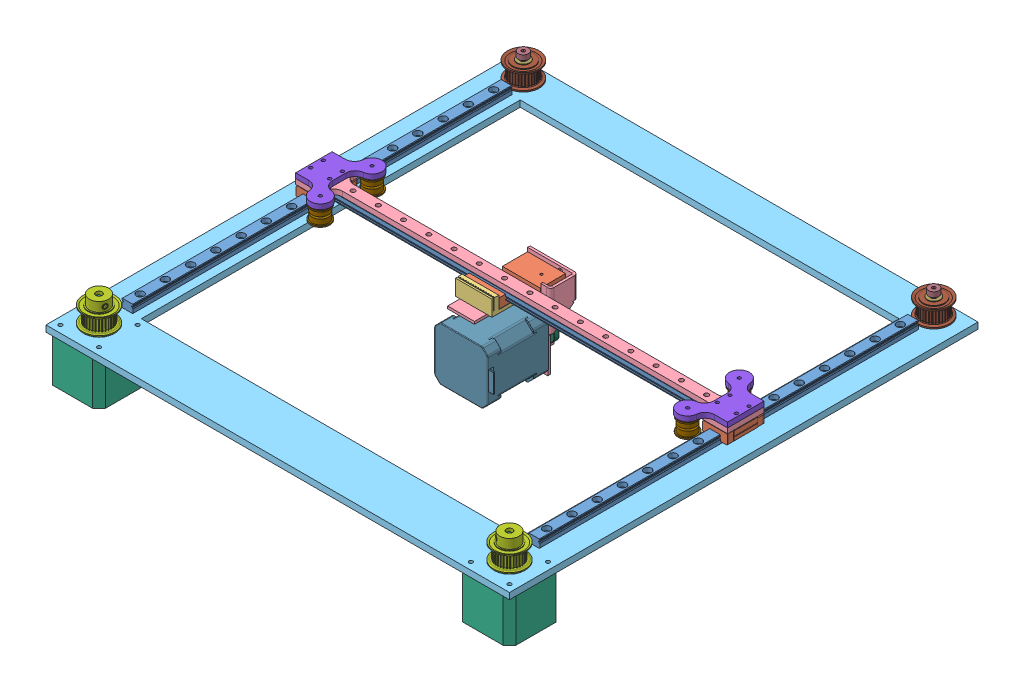
SolidWorks assembly XY, configuration Default. Lengths in mm.
Overall size (367 74.55 374.3).
68 component instances, 22 part files, 46 mates.
Components (placement in the parent):
- Y Rail-1: Y Rail [Default] at (-8.0434 -13.2339 12.0464) size (20 10.1 300)
  - MGN9-300MM-1: MGN9-300MM [Default] at (68.4102 185.8946 388.0774) size (9 6.6 300)
  - MGN9-1: MGN9 [Default] at (68.4102 185.8946 227.9447) size (20 8.05 28.9)
- Y Rail-2: Y Rail [Default] at (313.9566 -13.2339 12.0464) size (20 10.1 300)
  - MGN9-300MM-1: MGN9-300MM [Default] at (68.4102 185.8946 388.0774) size (9 6.6 300)
  - MGN9-1: MGN9 [Default] at (68.4102 185.8946 227.9447) size (20 8.05 28.9)
- X Rail-1: X Rail [Default] at (456.9443 355.5553 308.4012) x (0 0 -1) z (-1 0 0) size (25.38 12.6 300)
  - MGN9-300MM-1: MGN9-300MM [Default] at (68.4102 185.8946 388.0774) size (9 6.6 300)
  - MGN9-1: MGN9 [Default] at (68.4102 185.8946 264.6487) size (20 8.05 28.9)
  - X Carriage-1: X Carriage [Default] at (68.4102 189.3946 264.6487) x (1 0 0) z (0 1 0) size (25.38 28.9 12.5)
- X Support-1: X Support [Default] at (60.3668 176.1607 239.991) x (1 0 0) z (0 1 0) size (342 28.9 4)
- XY PLate-1: XY PLate [Default] at (378.8668 162.1607 597.6238) x (1 0 0) z (0 -1 0) size (367 371 5)
- Nema17-1: Nema17 [Default] at (77.8477 127.4107 443.2623) x (1 0 0) z (0 1 0) size (42 42 57.75)
- GT32TPulley-1: GT32TPulley [Default] at (58.8668 180.0607 418.6238) x (0.954377 0 0.298606) z (0 1 0) size (25.4 25.4 20.6)
- Nema17-2: Nema17 [Default] at (402.8477 127.4107 443.2623) x (1 0 0) z (0 1 0) size (42 42 57.75)
- GT32TPulley-2: GT32TPulley [Default] at (383.8668 180.0607 418.6238) x (-0.801635 0 -0.597814) z (0 1 0) size (25.4 25.4 20.6)
- BearingMount-1: BearingMount [Default] at (60.3668 180.1607 239.991) x (1 0 0) z (0 1 0) size (33.44 56.76 4)
- Idler Assembly-1: Idler Assembly [Default] at (85.5746 172.2269 208.7013) x (0 1 0) z (0 0 1) size (13.2 19.59 19.59)
  - F624ZZ-1: F624ZZ [Default] at (7.719 9.6467 10.7874) size (5 15 15)
  - M4 Washer-1: M4 Washer [Default] at (1.3338 9.6467 10.7874) x (0 -1 0) z (0 0 1) size (8.85 0.8 8.85)
  - M4 Washer-2: M4 Washer [Default] at (0.5338 9.6467 10.7874) x (0 -1 0) z (0 0 1) size (8.85 0.8 8.85)
  - F624ZZ-3: F624ZZ [Default] at (-5.0514 9.6467 10.7874) x (-1 0 0) z (0 -0.924225 -0.381849) size (5 15 15)
  - M4 Washer-3: M4 Washer [Default] at (-5.2662 9.6467 10.7874) x (0 -1 0) z (0 0 1) size (8.85 0.8 8.85)
  - M4 Washer-4: M4 Washer [Default] at (7.1338 9.6467 10.7874) x (0 -1 0) z (0 0 1) size (8.85 0.8 8.85)
- Idler Assembly-2: Idler Assembly [Default] at (85.5746 172.2269 249.7059) x (0 1 0) z (0 0 1) size (13.2 19.59 19.59)
  - F624ZZ-1: F624ZZ [Default] at (7.719 9.6467 10.7874) size (5 15 15)
  - M4 Washer-1: M4 Washer [Default] at (1.3338 9.6467 10.7874) x (0 -1 0) z (0 0 1) size (8.85 0.8 8.85)
  - M4 Washer-2: M4 Washer [Default] at (0.5338 9.6467 10.7874) x (0 -1 0) z (0 0 1) size (8.85 0.8 8.85)
  - F624ZZ-3: F624ZZ [Default] at (-5.0514 9.6467 10.7874) x (-1 0 0) z (0 -0.924225 -0.381849) size (5 15 15)
  - M4 Washer-3: M4 Washer [Default] at (-5.2662 9.6467 10.7874) x (0 -1 0) z (0 0 1) size (8.85 0.8 8.85)
  - M4 Washer-4: M4 Washer [Default] at (7.1338 9.6467 10.7874) x (0 -1 0) z (0 0 1) size (8.85 0.8 8.85)
- BearingMount-2: BearingMount [Default] at (382.3668 184.1607 239.991) x (-1 0 0) z (0 -1 0) size (33.44 56.76 4)
- Idler Assembly-3: Idler Assembly [Default] at (357.1591 174.8945 208.7013) x (0 -1 0) z (0 0 1) size (13.2 19.59 19.59)
  - F624ZZ-1: F624ZZ [Default] at (7.719 9.6467 10.7874) size (5 15 15)
  - M4 Washer-1: M4 Washer [Default] at (1.3338 9.6467 10.7874) x (0 -1 0) z (0 0 1) size (8.85 0.8 8.85)
  - M4 Washer-2: M4 Washer [Default] at (0.5338 9.6467 10.7874) x (0 -1 0) z (0 0 1) size (8.85 0.8 8.85)
  - F624ZZ-3: F624ZZ [Default] at (-5.0514 9.6467 10.7874) x (-1 0 0) z (0 -0.924225 -0.381849) size (5 15 15)
  - M4 Washer-3: M4 Washer [Default] at (-5.2662 9.6467 10.7874) x (0 -1 0) z (0 0 1) size (8.85 0.8 8.85)
  - M4 Washer-4: M4 Washer [Default] at (7.1338 9.6467 10.7874) x (0 -1 0) z (0 0 1) size (8.85 0.8 8.85)
- Idler Assembly-4: Idler Assembly [Default] at (357.1591 174.8945 249.7059) x (0 -1 0) z (0 0 1) size (13.2 19.59 19.59)
  - F624ZZ-1: F624ZZ [Default] at (7.719 9.6467 10.7874) size (5 15 15)
  - M4 Washer-1: M4 Washer [Default] at (1.3338 9.6467 10.7874) x (0 -1 0) z (0 0 1) size (8.85 0.8 8.85)
  - M4 Washer-2: M4 Washer [Default] at (0.5338 9.6467 10.7874) x (0 -1 0) z (0 0 1) size (8.85 0.8 8.85)
  - F624ZZ-3: F624ZZ [Default] at (-5.0514 9.6467 10.7874) x (-1 0 0) z (0 -0.924225 -0.381849) size (5 15 15)
  - M4 Washer-3: M4 Washer [Default] at (-5.2662 9.6467 10.7874) x (0 -1 0) z (0 0 1) size (8.85 0.8 8.85)
  - M4 Washer-4: M4 Washer [Default] at (7.1338 9.6467 10.7874) x (0 -1 0) z (0 0 1) size (8.85 0.8 8.85)
- Y Idler-1: Y Idler [Default] at (38.2356 173.3081 63.6616) x (0 -1 0) z (0 0 1) size (14.3 25 25)
  - Y Axis Idlergpa32gt2090_a_h6_2_03-1: Y Axis Idlergpa32gt2090_a_h6_2_03 [Default] at (-0.0026 20.6312 18.9623) size (13.3 25 25)
  - GFM-0506-06-1: GFM-0506-06 [Default] at (7.1474 20.6312 18.9623) x (0 0 1) z (-1 0 0) size (10 10 6)
  - GFM-0506-06-2: GFM-0506-06 [Default] at (-7.1526 20.6312 18.9623) x (0 0 -1) z (1 0 0) size (10 10 6)
- M4x16mmshoulderscrew-1: M4x16mmshoulderscrew [Default] at (58.8668 186.1607 82.6238) x (0 -1 0) z (0 0 1) size (25 8 8)
- Y Idler-2: Y Idler [Default] at (356.2237 173.3133 87.2143) x (0 1 0) z (0.546944 0 -0.837169) size (14.3 25 25)
  - Y Axis Idlergpa32gt2090_a_h6_2_03-1: Y Axis Idlergpa32gt2090_a_h6_2_03 [Default] at (-0.0026 20.6312 18.9623) size (13.3 25 25)
  - GFM-0506-06-1: GFM-0506-06 [Default] at (7.1474 20.6312 18.9623) x (0 0 1) z (-1 0 0) size (10 10 6)
  - GFM-0506-06-2: GFM-0506-06 [Default] at (-7.1526 20.6312 18.9623) x (0 0 -1) z (1 0 0) size (10 10 6)
- M4x16mmshoulderscrew-2: M4x16mmshoulderscrew [Default] at (383.8668 186.1607 82.6238) x (0 -1 0) z (0 0 1) size (25 8 8)
- Production drive 1-1: Production drive 1 [Default] at (202.0208 138.0107 227.1016) size (46.3 64.5 70)
  - 400515-1: 400515 [Default] at origin size (46.3 42.3 70)
  - Bearing 3ID 10OD 4W-1: Bearing 3ID 10OD 4W [Default] at (12.205 0 -10) size (11.5 11.5 4)
  - Part1-2: Part1 [Default] at (0 0 -10) size (12.17 12.03 4)
  - Filament-1: Filament [Default] at (5.6 0 -10) x (0 0 -1) z (1 0 0) size (1.71 50 1.71)
  - 51115K100-1: 51115K100 [51115K1] at (5.6 -24.95 -10) x (0 1 0) z (1 0 0) size (17.94 9.24 8)
  - Scoop-1: Scoop [Default] at (5.6 6 -10) x (0.994129 0 0.1082) z (-0.1082 0 0.994129) size (9.24 12 8)
  - Cooler-1: Cooler [Default] at (-0.3 29.5 -10) x (1 0 0) z (0 0 -1) size (30 14 20)
  - 51115K100-2: 51115K100 [51115K1] at (-10.1812 8.8 -4.8812) x (0 1 0) z (0.997081 0 0.076353) size (17.94 9.24 8)
  - 51115K100-3: 51115K100 [51115K1] at (-10.1812 8.8 -15.1188) x (0 1 0) z (0.997081 0 0.076353) size (17.94 9.24 8)
  - Stud connector-1: Stud connector [Default] at (5.6 21 -10) x (0.951034 0 0.309086) z (0.309086 0 -0.951034) size (9.24 15 8)
  - Part9^Production drive 1-1: Part9^Production drive 1 [Default] at (0 0 -2) x (-1 0 0) z (0 -1 0) size (43.3 60 60.15) (virtual)
Mates (geometry in assembly coordinates):
- Coincident1: coincident aligned: plane of Y Rail-1/MGN9-300MM-1 through (64.4668 172.6607 100.1238) normal (0 1 0); plane of Y Rail-2/MGN9-300MM-1 through (386.4668 172.6607 100.1238) normal (0 1 0)
- Coincident2: coincident aligned: plane of Y Rail-1/MGN9-300MM-1 through (60.3668 172.6607 397.6238) normal (0 0 1); plane of Y Rail-2/MGN9-300MM-1 through (382.3668 172.6607 397.6238) normal (0 0 1)
- Coincident3: coincident aligned: plane of Y Rail-1/MGN9-1 through (60.3668 176.1607 239.991) normal (0 1 0); plane of X Rail-1/MGN9-300MM-1 through (368.8668 176.1607 244.491) normal (0 1 0)
- Distance1: distance = 1 mm anti-aligned: plane of X Rail-1/MGN9-300MM-1 through (71.3668 169.6607 239.991) normal (-1 0 0); plane of Y Rail-1/MGN9-1 through (70.3668 175.8607 230.541) normal (1 0 0)
- Distance2: distance = 9.95 mm aligned: plane of Y Rail-1/MGN9-1 through (60.3668 172.6607 254.441) normal (0 0 1); plane of X Rail-1/MGN9-300MM-1 through (368.8668 170.0607 244.491) normal (0 0 1)
- Distance3: distance = 1 mm anti-aligned: plane of Y Rail-2/MGN9-1 through (372.3668 172.6607 239.991) normal (-1 0 0); plane of X Rail-1/MGN9-300MM-1 through (371.3668 171.4075 243.441) normal (1 0 0)
- InPlace1: in place: plane of ? through (60.3668 176.1607 276.6951) normal (0 1 0); plane of ? through (0 176.1607 0) normal (0 1 0); moOrthogonalPlaneRef_w of ? through (60.3668 176.1607 276.6951) normal (0 1 0); plane of ? through (0 176.1607 0) normal (0 0 -1); plane of ? through (60.3668 176.1607 276.6951) normal (0 1 0); line of ? through (-55 0 176.1607) axis (0 1 0); plane of Y Rail-1/MGN9-1 through (60.3668 176.1607 239.991) normal (0 1 0); unknown of X Support-1
- Coincident7: coincident aligned: plane of Y Rail-1/MGN9-1; plane of X Support-1
- Coincident8: coincident aligned: moOrthogonalPlaneRef_w of Y Rail-1/MGN9-1 through (60.3668 176.1607 239.991) normal (0 0 -1); plane of X Support-1 through (60.3668 176.1607 239.991) normal (0 0 -1)
- Coincident9: coincident anti-aligned: moOrthogonalPlaneRef_w of Y Rail-1/MGN9-1 through (60.3668 176.1607 239.991) normal (-1 0 0); plane of X Support-1
- Coincident4: coincident anti-aligned: plane of Y Rail-1/MGN9-300MM-1 through (55.8668 166.1607 100.1238) normal (0 -1 0); plane of XY PLate-1 through (378.8668 166.1607 597.6238) normal (0 1 0)
- Coincident5: coincident: plane of Y Rail-1/MGN9-300MM-1 through (56.9168 170.9139 97.6238) normal (0 0 -1); line of XY PLate-1 through (371.3668 161.1607 97.6238) axis (-1 0 0)
- Coincident6: coincident anti-aligned: plane of XY PLate-1 through (378.8668 161.1607 597.6238) normal (0 -1 0); plane of Nema17-1 through (77.8477 161.1607 443.2623) normal (0 1 0)
- Parallel1: parallel aligned: plane of XY PLate-1 through (378.8668 161.1607 439.6238) normal (0 0 1); plane of Nema17-1 through (42.8668 161.1607 439.6238) normal (0 0 1)
- Coincident8: coincident aligned: plane of Nema17-1 through (77.8477 161.1607 443.2623) normal (0 1 0); plane of Nema17-2 through (402.8477 161.1607 443.2623) normal (0 1 0)
- Coincident9: coincident aligned: plane of Nema17-1 through (42.8668 161.1607 439.6238) normal (0 0 1); plane of Nema17-2 through (367.8668 161.1607 439.6238) normal (0 0 1)
- Distance6: distance = 12.5 mm aligned: plane of Y Rail-1/MGN9-1 through (50.3668 172.6607 239.991) normal (-1 0 0); plane of Nema17-1 through (37.8668 161.1607 402.6238) normal (-1 0 0)
- Distance7: distance = 0 mm aligned: plane of Nema17-1 through (42.8668 161.1607 439.6238) normal (0 0 1); plane of XY PLate-1 through (378.8668 161.1607 439.6238) normal (0 0 1)
- Distance8: distance = 2.15 mm aligned: plane of GT32TPulley-1 through (58.8668 168.3107 418.6238) normal (0 1 0); plane of XY PLate-1 through (378.8668 166.1607 597.6238) normal (0 1 0)
- Concentric3: concentric anti-aligned: cylinder of Nema17-1 through (58.8668 163.1607 418.6238) axis (0 -1 0) radius 11; cylinder of GT32TPulley-1 through (58.8668 167.0607 418.6238) axis (0 1 0) radius 2.5
- Concentric4: concentric anti-aligned: cylinder of Nema17-2 through (383.8668 185.1607 418.6238) axis (0 -1 0) radius 2.5; cylinder of GT32TPulley-2 through (383.8668 167.0607 418.6238) axis (0 1 0) radius 2.5
- Distance9: distance = 12.5 mm aligned: plane of Nema17-2 through (404.8668 161.1607 402.6238) normal (1 0 0); plane of Y Rail-2/MGN9-1 through (392.3668 175.8607 230.541) normal (1 0 0)
- Coincident14: coincident anti-aligned: circle of GT32TPulley-1; plane of GT32TPulley-2 through (383.8668 187.5607 418.6238) normal (0 1 0)
- Concentric5: concentric aligned: cylinder of X Support-1 through (52.8668 180.1607 234.991) axis (0 -1 0) radius 1.25; cylinder of BearingMount-1 through (52.8668 184.1607 234.991) axis (0 -1 0) radius 1.25
- Concentric6: concentric anti-aligned: cylinder of Y Rail-1/MGN9-1 through (67.8668 176.1607 244.991) axis (0 1 0) radius 1.25; cylinder of BearingMount-1 through (67.8668 184.1607 244.991) axis (0 -1 0) radius 1.25
- Coincident15: coincident anti-aligned: plane of BearingMount-1 through (75.9278 180.1607 260.4933) normal (0 -1 0); plane of Idler Assembly-1/M4 Washer-4 through (75.9278 180.1607 219.4887) normal (0 1 0)
- Concentric7: concentric anti-aligned: cylinder of BearingMount-1 through (75.9278 184.1607 219.4887) axis (0 -1 0) radius 7.88; circle of Idler Assembly-1/M4 Washer-3
- Coincident16: coincident anti-aligned: plane of BearingMount-1 through (75.9278 180.1607 260.4933) normal (0 -1 0); plane of Idler Assembly-2/M4 Washer-4 through (75.9278 180.1607 260.4933) normal (0 1 0)
- Concentric8: concentric anti-aligned: cylinder of BearingMount-1 through (75.9278 184.1607 260.4933) axis (0 -1 0) radius 7.88; cylinder of Idler Assembly-2/F624ZZ-1 through (75.9278 179.9459 260.4933) axis (0 1 0) radius 6.5
- Coincident17: coincident anti-aligned: plane of X Support-1 through (60.3668 180.1607 239.991) normal (0 1 0); plane of BearingMount-2 through (366.8058 180.1607 260.4933) normal (0 -1 0)
- Concentric9: concentric aligned: cylinder of X Support-1 through (389.8668 180.1607 244.991) axis (0 -1 0) radius 1.25; circle of BearingMount-2
- Concentric10: concentric aligned: circle of X Support-1; circle of BearingMount-2
- Coincident18: coincident anti-aligned: plane of BearingMount-2 through (366.8058 180.1607 260.4933) normal (0 -1 0); plane of Idler Assembly-3/M4 Washer-3 through (366.8058 180.1607 219.4887) normal (0 1 0)
- Concentric11: concentric anti-aligned: circle of BearingMount-2; cylinder of Idler Assembly-3/F624ZZ-1 through (366.8058 167.1755 219.4887) axis (0 -1 0) radius 2
- Coincident19: coincident anti-aligned: plane of BearingMount-2 through (366.8058 180.1607 260.4933) normal (0 -1 0); plane of Idler Assembly-4/M4 Washer-3 through (366.8058 180.1607 260.4933) normal (0 1 0)
- Concentric12: concentric aligned: cylinder of BearingMount-2 through (366.8058 180.1607 260.4933) axis (0 1 0) radius 7.88; cylinder of Idler Assembly-4/F624ZZ-3 through (366.8058 179.9459 260.4933) axis (0 1 0) radius 6.5
- Coincident20: coincident aligned: plane of GT32TPulley-1 through (58.8668 168.3107 418.6238) normal (0 1 0); plane of Y Idler-1/Y Axis Idlergpa32gt2090_a_h6_2_03-1 through (68.4058 168.3107 82.6238) normal (0 1 0)
- Coincident21: coincident anti-aligned: plane of X Support-1 through (60.3668 180.1607 239.991) normal (0 1 0); plane of BearingMount-1 through (75.9278 180.1607 260.4933) normal (0 -1 0)
- Concentric13: concentric anti-aligned: cylinder of XY PLate-1 through (58.8668 166.1607 82.6238) axis (0 -1 0) radius 2; cylinder of Y Idler-1/GFM-0506-06-2 through (58.8668 177.4607 82.6238) axis (0 1 0) radius 2.5
- Coincident22: coincident aligned: plane of XY PLate-1 through (378.8668 166.1607 597.6238) normal (0 1 0); circle of M4x16mmshoulderscrew-1
- Concentric14: concentric aligned: cylinder of Y Idler-1/GFM-0506-06-2 through (58.8668 177.4607 82.6238) axis (0 1 0) radius 2.5; cylinder of M4x16mmshoulderscrew-1 through (58.8668 186.1607 82.6238) axis (0 1 0) radius 2.5
- Coincident23: coincident aligned: plane of Y Idler-1/GFM-0506-06-2 through (58.8668 180.4607 78.8738) normal (0 1 0); plane of Y Idler-2/GFM-0506-06-1 through (385.9179 180.4607 79.4844) normal (0 1 0)
- Concentric15: concentric aligned: cylinder of XY PLate-1 through (383.8668 166.1607 82.6238) axis (0 -1 0) radius 2; cylinder of Y Idler-2/GFM-0506-06-2 through (383.8668 169.1607 82.6238) axis (0 -1 0) radius 2.5
- Coincident24: coincident aligned: plane of XY PLate-1 through (378.8668 166.1607 597.6238) normal (0 1 0); circle of M4x16mmshoulderscrew-2
- Concentric16: concentric anti-aligned: circle of Y Idler-2/GFM-0506-06-1; cylinder of M4x16mmshoulderscrew-2 through (383.8668 186.1607 82.6238) axis (0 1 0) radius 2.5
- Coincident26: coincident anti-aligned: plane of X Rail-1/X Carriage-1 through (192.2956 163.6607 239.991) normal (0 -1 0); plane of Production drive 1-1/Part9^Production drive 1-1 through (202.0208 163.6607 225.1016) normal (0 1 0)
